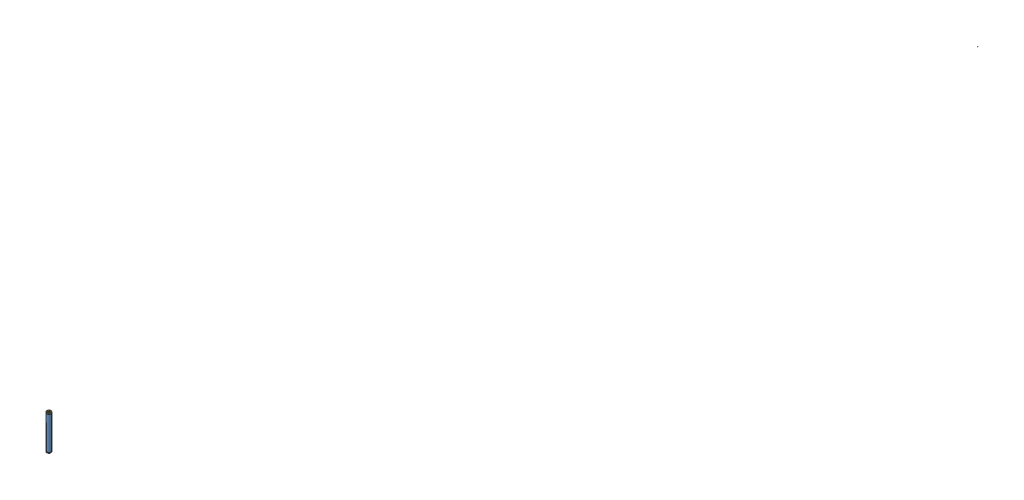
SolidWorks assembly 10005-R03_ASSEMBLY_PRESSURANT_BULK_HEAD, configuration Default. Lengths in mm.
Overall size (37041.81 28501.64 31536.85).
27 component instances, 9 part files, 57 mates.
Components (placement in the parent):
- 14008_R01_AIRFRAME_SEC2-1: 14008_R01_AIRFRAME_SEC2 [Default] at (0 -130.429 0) x (0.978801 0 -0.204816) z (0 1 0) size (304.8 304.8 2413)
- 15001-R06_PRESSURANT_TANK-2: 15001-R06_PRESSURANT_TANK [Default] at origin size (284.43 2421.28 284.43)
- 15005-R06_PRESSURANT_TANK_BULKHEAD_TOP-1: 15005-R06_PRESSURANT_TANK_BULKHEAD_TOP [Default] at (0 2244.471 0) x (0.978029 0 -0.20847) z (0.20847 0 0.978029) size (304.8 107.95 304.8)
- 15006-R03_PRESSURANT_TANK_BULKHEAD_BOT-1: 15006-R03_PRESSURANT_TANK_BULKHEAD_BOT [Default] at (0 -193.929 0) x (0.978801 0 -0.204816) z (0.204816 0 0.978801) size (304.8 101.6 304.8)
- 16001-R01_THREADED_ROD-1: 16001-R01_THREADED_ROD [Default] at (-49.1485 2237.1691 103.1936) x (-0.882772 0 -0.469801) z (0.469801 0 -0.882772) size (15.88 76.2 15.88)
- 16001-R01_THREADED_ROD-2: 16001-R01_THREADED_ROD [Default] at (-113.9425 2237.1691 9.0329) x (-0.245118 0 -0.969493) z (0.969493 0 -0.245118) size (15.88 76.2 15.88)
- 16001-R01_THREADED_ROD-3: 16001-R01_THREADED_ROD [Default] at (49.1485 2237.1691 -103.1936) x (-0.270273 0 -0.962784) z (0.962784 0 -0.270273) size (15.88 76.2 15.88)
- 16001-R01_THREADED_ROD-4: 16001-R01_THREADED_ROD [Default] at (-64.794 2237.1691 -94.1606) x (0.316148 0 0.94871) z (-0.94871 0 0.316148) size (15.88 76.2 15.88)
- 16001-R01_THREADED_ROD-5: 16001-R01_THREADED_ROD [Default] at (64.794 2237.1691 94.1606) x (-0.104252 0 -0.994551) z (0.994551 0 -0.104252) size (15.88 76.2 15.88)
- 16001-R01_THREADED_ROD-6: 16001-R01_THREADED_ROD [Default] at (113.9425 2237.1691 -9.0329) x (-0.171403 0 0.985201) z (-0.985201 0 -0.171403) size (15.88 76.2 15.88)
- 91845A325_TYPE 18-8 STAINLESS STEEL HEX NUT-1: 91845A325_TYPE 18-8 STAINLESS STEEL HEX NUT [91845A325] at (-49.1485 2267.5301 103.1936) x (-0.503464 0 0.864016) z (0 1 0) size (23.81 27.5 16.67)
- 91845A325_TYPE 18-8 STAINLESS STEEL HEX NUT-2: 91845A325_TYPE 18-8 STAINLESS STEEL HEX NUT [91845A325] at (-64.794 2244.1144 -94.1606) x (0.092164 0 -0.995744) z (0 -1 0) size (23.81 27.5 16.67)
- 91845A325_TYPE 18-8 STAINLESS STEEL HEX NUT-3: 91845A325_TYPE 18-8 STAINLESS STEEL HEX NUT [91845A325] at (64.794 2267.5301 94.1606) x (0.627589 0 0.778545) z (0 1 0) size (23.81 27.5 16.67)
- 91845A325_TYPE 18-8 STAINLESS STEEL HEX NUT-4: 91845A325_TYPE 18-8 STAINLESS STEEL HEX NUT [91845A325] at (-64.794 2267.5301 -94.1606) x (0.785718 0 0.618585) z (0 1 0) size (23.81 27.5 16.67)
- 91845A325_TYPE 18-8 STAINLESS STEEL HEX NUT-5: 91845A325_TYPE 18-8 STAINLESS STEEL HEX NUT [91845A325] at (64.794 2244.1144 94.1606) x (1 0 0) z (0 -1 0) size (23.81 27.5 16.67)
- 91845A325_TYPE 18-8 STAINLESS STEEL HEX NUT-6: 91845A325_TYPE 18-8 STAINLESS STEEL HEX NUT [91845A325] at (113.9425 2267.5301 -9.0329) x (0.985928 0 0.167168) z (0 1 0) size (23.81 27.5 16.67)
- 91845A325_TYPE 18-8 STAINLESS STEEL HEX NUT-7: 91845A325_TYPE 18-8 STAINLESS STEEL HEX NUT [91845A325] at (-113.9425 2267.5301 9.0329) x (0.702174 0 0.712005) z (0 1 0) size (23.81 27.5 16.67)
- 91845A325_TYPE 18-8 STAINLESS STEEL HEX NUT-8: 91845A325_TYPE 18-8 STAINLESS STEEL HEX NUT [91845A325] at (-113.9425 2244.1144 9.0329) x (0.823932 0 0.566689) z (0 -1 0) size (23.81 27.5 16.67)
- 91845A325_TYPE 18-8 STAINLESS STEEL HEX NUT-9: 91845A325_TYPE 18-8 STAINLESS STEEL HEX NUT [91845A325] at (24135.9982 19491.1032 -20839.0581) size (23.81 27.5 16.67)
- 91845A325_TYPE 18-8 STAINLESS STEEL HEX NUT-10: 91845A325_TYPE 18-8 STAINLESS STEEL HEX NUT [91845A325] at (36849.0841 28293.964 -31349.08) size (23.81 27.5 16.67)
- 91845A325_TYPE 18-8 STAINLESS STEEL HEX NUT-11: 91845A325_TYPE 18-8 STAINLESS STEEL HEX NUT [91845A325] at (-49.1485 2244.1144 103.1936) x (-0.982062 0 -0.188561) z (0 -1 0) size (23.81 27.5 16.67)
- 91845A325_TYPE 18-8 STAINLESS STEEL HEX NUT-12: 91845A325_TYPE 18-8 STAINLESS STEEL HEX NUT [91845A325] at (113.9425 2244.1144 -9.0329) x (1 0 0) z (0 -1 0) size (23.81 27.5 16.67)
- 91845A325_TYPE 18-8 STAINLESS STEEL HEX NUT-13: 91845A325_TYPE 18-8 STAINLESS STEEL HEX NUT [91845A325] at (49.1485 2244.1144 -103.1936) x (1 0 0) z (0 -1 0) size (23.81 27.5 16.67)
- 91845A325_TYPE 18-8 STAINLESS STEEL HEX NUT-14: 91845A325_TYPE 18-8 STAINLESS STEEL HEX NUT [91845A325] at (49.1485 2267.5301 -103.1936) x (0.974788 0 -0.223134) z (0 1 0) size (23.81 27.5 16.67)
- 15007-R05_VIBRATION_ABSORBER-1: 15007-R05_VIBRATION_ABSORBER [Default] at (0 382.2802 0) size (152.4 34.84 152.4)
- 15008-R03_LOWER_VIBRATION_ABSORBER-1: 15008-R03_LOWER_VIBRATION_ABSORBER [Default] at (0 1729.74 0) x (-0.855264 0 -0.518192) z (-0.518192 0 0.855264) size (152.4 32.58 152.4)
- 15002-R02_PRESSURANT_TANK_RETAINER-1: 15002-R02_PRESSURANT_TANK_RETAINER [Default] at (73.1139 2251.0598 122.6947) x (0.996872 0 -0.079028) z (0.079028 0 0.996872) size (279.4 9.53 279.4)
Mates (geometry in assembly coordinates):
- Concentric21: concentric: cylinder of 14008_R01_AIRFRAME_SEC2-1 through (0 -130.429 0) axis (0 1 0) radius 149.225; cylinder of 15006-R03_PRESSURANT_TANK_BULKHEAD_BOT-1 through (0 -130.429 0) axis (0 1 0) radius 149.225
- Coincident11: coincident: plane of 14008_R01_AIRFRAME_SEC2-1 through (0 -130.429 0) normal (0 -1 0); plane of 15006-R03_PRESSURANT_TANK_BULKHEAD_BOT-1 through (0 -130.429 0) normal (0 1 0)
- Concentric22: concentric: cylinder of 14008_R01_AIRFRAME_SEC2-1 through (-104.2587 -111.379 159.4377) axis (0.54729 0 -0.836943) radius 3.175; cylinder of 15006-R03_PRESSURANT_TANK_BULKHEAD_BOT-1 through (-81.6693 -111.379 124.8928) axis (-0.54729 0 0.836943) radius 3.2639
- Concentric24: concentric: cylinder of 14008_R01_AIRFRAME_SEC2-1 through (0 -130.429 0) axis (0 1 0) radius 149.225; cylinder of 15005-R06_PRESSURANT_TANK_BULKHEAD_TOP-1 through (0 2282.571 0) axis (0 -1 0) radius 149.225
- Coincident12: coincident: plane of 14008_R01_AIRFRAME_SEC2-1 through (0 2282.571 0) normal (0 1 0); plane of 15005-R06_PRESSURANT_TANK_BULKHEAD_TOP-1 through (0 2282.571 0) normal (0 -1 0)
- Parallel1: parallel: cylinder of 14008_R01_AIRFRAME_SEC2-1 through (-265.0239 2263.521 55.4568) axis (0.978801 0 -0.204816) radius 3.175; cylinder of 15005-R06_PRESSURANT_TANK_BULKHEAD_TOP-1 through (-146.0615 2263.5234 30.5636) axis (-0.978801 0 0.204816) radius 3.2639
- Concentric31: concentric: cylinder of 15005-R06_PRESSURANT_TANK_BULKHEAD_TOP-1 through (64.794 2298.446 94.1606) axis (0 1 0) radius 7.9375; cylinder of 16001-R01_THREADED_ROD-5 through (64.794 2313.3691 94.1606) axis (0 -1 0) radius 7.9375
- Concentric32: concentric: cylinder of 16001-R01_THREADED_ROD-1 through (-49.1485 2313.3691 103.1936) axis (0 -1 0) radius 7.9375; cylinder of 15005-R06_PRESSURANT_TANK_BULKHEAD_TOP-1 through (-49.1485 2298.446 103.1936) axis (0 1 0) radius 7.9375
- Concentric34: concentric: cylinder of 16001-R01_THREADED_ROD-2 through (-113.9425 2313.3691 9.0329) axis (0 -1 0) radius 7.9375; cylinder of 15005-R06_PRESSURANT_TANK_BULKHEAD_TOP-1 through (-113.9425 2298.446 9.0329) axis (0 1 0) radius 7.9375
- Concentric36: concentric: cylinder of 15005-R06_PRESSURANT_TANK_BULKHEAD_TOP-1 through (113.9425 2298.446 -9.0329) axis (0 1 0) radius 7.9375; cylinder of 16001-R01_THREADED_ROD-6 through (113.9425 2313.3691 -9.0329) axis (0 -1 0) radius 7.9375
- Concentric38: concentric: cylinder of 16001-R01_THREADED_ROD-4 through (-64.794 2313.3691 -94.1606) axis (0 -1 0) radius 7.9375; cylinder of 15005-R06_PRESSURANT_TANK_BULKHEAD_TOP-1 through (-64.794 2298.446 -94.1606) axis (0 1 0) radius 7.9375
- Concentric40: concentric: cylinder of 16001-R01_THREADED_ROD-3 through (49.1485 2313.3691 -103.1936) axis (0 -1 0) radius 7.9375; cylinder of 15005-R06_PRESSURANT_TANK_BULKHEAD_TOP-1 through (49.1485 2298.446 -103.1936) axis (0 1 0) radius 7.9375
- Concentric42: concentric: cylinder of 16001-R01_THREADED_ROD-1 through (-49.1485 2313.3691 103.1936) axis (0 -1 0) radius 7.9375; cylinder of 91845A325_TYPE 18-8 STAINLESS STEEL HEX NUT-11 through (-49.1485 2237.1691 103.1936) axis (0 1 0) radius 7.9375
- Concentric43: concentric: cylinder of 16001-R01_THREADED_ROD-1 through (-49.1485 2313.3691 103.1936) axis (0 -1 0) radius 7.9375; cylinder of 91845A325_TYPE 18-8 STAINLESS STEEL HEX NUT-1 through (-49.1485 2274.4754 103.1936) axis (0 -1 0) radius 7.9375
- Concentric44: concentric: cylinder of 16001-R01_THREADED_ROD-2 through (-113.9425 2313.3691 9.0329) axis (0 -1 0) radius 7.9375; cylinder of 91845A325_TYPE 18-8 STAINLESS STEEL HEX NUT-8 through (-113.9425 2237.1691 9.0329) axis (0 1 0) radius 7.9375
- Coincident19: coincident: plane of 16001-R01_THREADED_ROD-2 through (-113.9425 2237.1691 9.0329) normal (0 -1 0); plane of 91845A325_TYPE 18-8 STAINLESS STEEL HEX NUT-8 through (-127.6479 2237.1691 7.9496) normal (0 -1 0)
- Concentric45: concentric: cylinder of 16001-R01_THREADED_ROD-2 through (-113.9425 2313.3691 9.0329) axis (0 -1 0) radius 7.9375; cylinder of 91845A325_TYPE 18-8 STAINLESS STEEL HEX NUT-7 through (-113.9425 2380.6216 9.0329) axis (0 -1 0) radius 7.9375
- Coincident21: coincident: plane of 16001-R01_THREADED_ROD-1 through (-49.1485 2237.1691 103.1936) normal (0 -1 0); plane of 91845A325_TYPE 18-8 STAINLESS STEEL HEX NUT-11 through (-36.1597 2237.1691 98.6879) normal (0 -1 0)
- Concentric46: concentric: cylinder of 16001-R01_THREADED_ROD-5 through (64.794 2313.3691 94.1606) axis (0 -1 0) radius 7.9375; cylinder of 91845A325_TYPE 18-8 STAINLESS STEEL HEX NUT-3 through (64.794 2274.4754 94.1606) axis (0 -1 0) radius 7.9375
- Concentric47: concentric: cylinder of 16001-R01_THREADED_ROD-5 through (64.794 2313.3691 94.1606) axis (0 -1 0) radius 7.9375; cylinder of 91845A325_TYPE 18-8 STAINLESS STEEL HEX NUT-5 through (64.794 2237.1691 94.1606) axis (0 1 0) radius 7.9375
- Coincident24: coincident: plane of 16001-R01_THREADED_ROD-5 through (64.794 2237.1691 94.1606) normal (0 -1 0); plane of 91845A325_TYPE 18-8 STAINLESS STEEL HEX NUT-5 through (52.8878 2237.1691 101.0347) normal (0 -1 0)
- Concentric48: concentric: cylinder of 16001-R01_THREADED_ROD-6 through (113.9425 2313.3691 -9.0329) axis (0 -1 0) radius 7.9375; cylinder of 91845A325_TYPE 18-8 STAINLESS STEEL HEX NUT-6 through (113.9425 2274.4754 -9.0329) axis (0 -1 0) radius 7.9375
- Concentric49: concentric: cylinder of 16001-R01_THREADED_ROD-6 through (113.9425 2313.3691 -9.0329) axis (0 -1 0) radius 7.9375; cylinder of 91845A325_TYPE 18-8 STAINLESS STEEL HEX NUT-12 through (113.9425 2237.1691 -9.0329) axis (0 1 0) radius 7.9375
- Coincident28: coincident: plane of 16001-R01_THREADED_ROD-6 through (113.9425 2237.1691 -9.0329) normal (0 -1 0); plane of 91845A325_TYPE 18-8 STAINLESS STEEL HEX NUT-12 through (102.0363 2237.1691 -2.1589) normal (0 -1 0)
- Concentric50: concentric: cylinder of 16001-R01_THREADED_ROD-4 through (-64.794 2313.3691 -94.1606) axis (0 -1 0) radius 7.9375; cylinder of 91845A325_TYPE 18-8 STAINLESS STEEL HEX NUT-4 through (-64.794 2274.4754 -94.1606) axis (0 -1 0) radius 7.9375
- Concentric51: concentric: cylinder of 16001-R01_THREADED_ROD-4 through (-64.794 2313.3691 -94.1606) axis (0 -1 0) radius 7.9375; cylinder of 91845A325_TYPE 18-8 STAINLESS STEEL HEX NUT-2 through (-64.794 2237.1691 -94.1606) axis (0 1 0) radius 7.9375
- Coincident31: coincident: plane of 16001-R01_THREADED_ROD-4 through (-64.794 2237.1691 -94.1606) normal (0 -1 0); plane of 91845A325_TYPE 18-8 STAINLESS STEEL HEX NUT-2 through (-59.0465 2237.1691 -81.6715) normal (0 -1 0)
- Concentric52: concentric: cylinder of 16001-R01_THREADED_ROD-3 through (49.1485 2313.3691 -103.1936) axis (0 -1 0) radius 7.9375; cylinder of 91845A325_TYPE 18-8 STAINLESS STEEL HEX NUT-13 through (49.1485 2237.1691 -103.1936) axis (0 1 0) radius 7.9375
- Coincident33: coincident: plane of 16001-R01_THREADED_ROD-3 through (49.1485 2237.1691 -103.1936) normal (0 -1 0); plane of 91845A325_TYPE 18-8 STAINLESS STEEL HEX NUT-13 through (37.2423 2237.1691 -96.3195) normal (0 -1 0)
- Concentric53: concentric: cylinder of 16001-R01_THREADED_ROD-3 through (49.1485 2313.3691 -103.1936) axis (0 -1 0) radius 7.9375; cylinder of 91845A325_TYPE 18-8 STAINLESS STEEL HEX NUT-14 through (49.1485 2274.4754 -103.1936) axis (0 -1 0) radius 7.9375
- Concentric54: concentric: sphere of 15001-R06_PRESSURANT_TANK-2; sphere of 15007-R05_VIBRATION_ABSORBER-1
- Coincident36: coincident: plane of 15001-R06_PRESSURANT_TANK-2 through (0 0 0) normal (0 0 1); plane of assembly through (0 0 0) normal (0 0 1)
- Coincident37: coincident: plane of 15001-R06_PRESSURANT_TANK-2 through (0 0 0) normal (0 1 0); plane of assembly through (0 0 0) normal (0 1 0)
- Coincident38: coincident: plane of 15001-R06_PRESSURANT_TANK-2 through (0 0 0) normal (1 0 0); plane of assembly through (0 0 0) normal (1 0 0)
- Coincident39: coincident: plane of 15006-R03_PRESSURANT_TANK_BULKHEAD_BOT-1 through (0 -139.954 0) normal (0 1 0); plane of 15008-R03_LOWER_VIBRATION_ABSORBER-1 through (59.7402 -139.954 36.1957) normal (0 -1 0)
- Concentric58: concentric: cylinder of 15006-R03_PRESSURANT_TANK_BULKHEAD_BOT-1 through (0 -193.929 0) axis (0 1 0) radius 69.85; cylinder of 15008-R03_LOWER_VIBRATION_ABSORBER-1 through (0 1679.382 0) axis (0 -1 0) radius 69.85
- Concentric59: concentric: sphere of 15001-R06_PRESSURANT_TANK-2; sphere of 15008-R03_LOWER_VIBRATION_ABSORBER-1
- Concentric60: concentric: cylinder of 15007-R05_VIBRATION_ABSORBER-1 through (0 432.6382 0) axis (0 1 0) radius 69.85; cylinder of 15002-R02_PRESSURANT_TANK_RETAINER-1 through (0 2260.5848 0) axis (0 -1 0) radius 69.85
- Coincident40: coincident: plane of 15007-R05_VIBRATION_ABSORBER-1 through (-69.85 2251.0598 0) normal (0 1 0); plane of 15002-R02_PRESSURANT_TANK_RETAINER-1 through (0 2251.0598 0) normal (0 -1 0)
- Concentric61: concentric: cylinder of 16001-R01_THREADED_ROD-2 through (-113.9425 2313.3691 9.0329) axis (0 -1 0) radius 7.9375; cylinder of 15002-R02_PRESSURANT_TANK_RETAINER-1 through (-113.9425 2251.0588 9.0329) axis (0 1 0) radius 7.9375
- Concentric62: concentric: cylinder of 16001-R01_THREADED_ROD-1 through (-49.1485 2313.3691 103.1936) axis (0 -1 0) radius 7.9375; cylinder of 15002-R02_PRESSURANT_TANK_RETAINER-1 through (-49.1485 2251.0588 103.1936) axis (0 1 0) radius 7.9375
- Coincident41: coincident: plane of 91845A325_TYPE 18-8 STAINLESS STEEL HEX NUT-1 through (-37.2148 2260.5848 96.3672) normal (0 -1 0); plane of 15002-R02_PRESSURANT_TANK_RETAINER-1 through (0 2260.5848 0) normal (0 1 0)
- Coincident43: coincident: plane of 91845A325_TYPE 18-8 STAINLESS STEEL HEX NUT-11 through (-36.1597 2251.0598 98.6879) normal (0 1 0); plane of 15002-R02_PRESSURANT_TANK_RETAINER-1 through (0 2251.0598 0) normal (0 -1 0)
- Concentric63: concentric: cylinder of 16001-R01_THREADED_ROD-4 through (-64.794 2313.3691 -94.1606) axis (0 -1 0) radius 7.9375; cylinder of 15002-R02_PRESSURANT_TANK_RETAINER-1 through (-64.794 2251.0588 -94.1606) axis (0 1 0) radius 7.9375
- Coincident44: coincident: plane of 91845A325_TYPE 18-8 STAINLESS STEEL HEX NUT-2 through (-59.0465 2251.0598 -81.6715) normal (0 1 0); plane of 15002-R02_PRESSURANT_TANK_RETAINER-1 through (0 2251.0598 0) normal (0 -1 0)
- Coincident45: coincident: plane of 91845A325_TYPE 18-8 STAINLESS STEEL HEX NUT-4 through (-69.8967 2260.5848 -106.9268) normal (0 -1 0); plane of 15002-R02_PRESSURANT_TANK_RETAINER-1 through (0 2260.5848 0) normal (0 1 0)
- Coincident46: coincident: plane of 91845A325_TYPE 18-8 STAINLESS STEEL HEX NUT-8 through (-127.6479 2251.0598 7.9496) normal (0 1 0); plane of 15002-R02_PRESSURANT_TANK_RETAINER-1 through (0 2251.0598 0) normal (0 -1 0)
- Concentric64: concentric: cylinder of 16001-R01_THREADED_ROD-3 through (49.1485 2313.3691 -103.1936) axis (0 -1 0) radius 7.9375; cylinder of 15002-R02_PRESSURANT_TANK_RETAINER-1 through (49.1485 2251.0588 -103.1936) axis (0 1 0) radius 7.9375
- Coincident47: coincident: plane of 91845A325_TYPE 18-8 STAINLESS STEEL HEX NUT-13 through (37.2423 2251.0598 -96.3195) normal (0 1 0); plane of 15002-R02_PRESSURANT_TANK_RETAINER-1 through (0 2251.0598 0) normal (0 -1 0)
- Coincident49: coincident: plane of 91845A325_TYPE 18-8 STAINLESS STEEL HEX NUT-14 through (36.0086 2260.5848 -107.2376) normal (0 -1 0); plane of 15002-R02_PRESSURANT_TANK_RETAINER-1 through (0 2260.5848 0) normal (0 1 0)
- Concentric65: concentric: cylinder of 16001-R01_THREADED_ROD-6 through (113.9425 2313.3691 -9.0329) axis (0 -1 0) radius 7.9375; cylinder of 15002-R02_PRESSURANT_TANK_RETAINER-1 through (113.9425 2251.0588 -9.0329) axis (0 1 0) radius 7.9375
- Coincident50: coincident: plane of 91845A325_TYPE 18-8 STAINLESS STEEL HEX NUT-12 through (102.0363 2251.0598 -2.1589) normal (0 1 0); plane of 15002-R02_PRESSURANT_TANK_RETAINER-1 through (0 2251.0598 0) normal (0 -1 0)
- Coincident51: coincident: plane of 91845A325_TYPE 18-8 STAINLESS STEEL HEX NUT-6 through (103.3529 2260.5848 -17.8006) normal (0 -1 0); plane of 15002-R02_PRESSURANT_TANK_RETAINER-1 through (0 2260.5848 0) normal (0 1 0)
- Concentric66: concentric: cylinder of 16001-R01_THREADED_ROD-5 through (64.794 2313.3691 94.1606) axis (0 -1 0) radius 7.9375; cylinder of 15002-R02_PRESSURANT_TANK_RETAINER-1 through (64.794 2251.0588 94.1606) axis (0 1 0) radius 7.9375
- Coincident52: coincident: plane of 91845A325_TYPE 18-8 STAINLESS STEEL HEX NUT-5 through (52.8878 2251.0598 101.0347) normal (0 1 0); plane of 15002-R02_PRESSURANT_TANK_RETAINER-1 through (0 2251.0598 0) normal (0 -1 0)
- Coincident53: coincident: plane of 91845A325_TYPE 18-8 STAINLESS STEEL HEX NUT-3 through (62.6735 2260.5848 80.577) normal (0 -1 0); plane of 15002-R02_PRESSURANT_TANK_RETAINER-1 through (0 2260.5848 0) normal (0 1 0)
- Coincident54: coincident: plane of 91845A325_TYPE 18-8 STAINLESS STEEL HEX NUT-7 through (-117.4084 2260.5848 -4.2712) normal (0 -1 0); plane of 15002-R02_PRESSURANT_TANK_RETAINER-1 through (0 2260.5848 0) normal (0 1 0)
